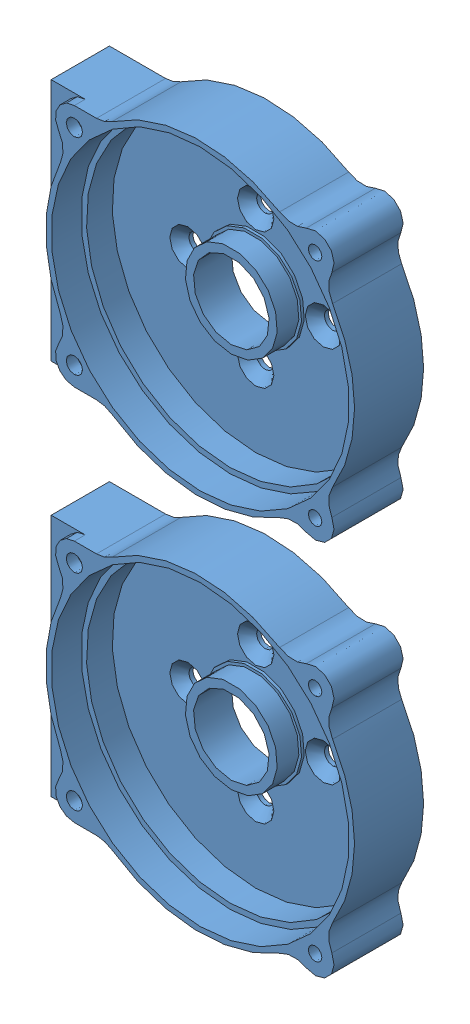
SolidWorks assembly cam3, configuration Default. Lengths in mm.
Overall size (59.75 130.14 32.25).
2 component instances, 1 part files, 3 mates.
Components (placement in the parent):
- Back Housing-2: Back Housing [Default] at (0.5773 -0.6602 10.4583) x (0 -1 0) z (0 0 -1) size (60.51 59.75 32.25)
- Back Housing-3: Back Housing [Default] at (0.5773 68.9622 10.4583) x (0 -1 0) z (0 0 -1) size (60.51 59.75 32.25)
Mates (geometry in assembly coordinates):
- Coincident1: coincident aligned: plane of Back Housing-2 through (-16.9227 -0.6602 10) normal (0 0 -1); plane of Back Housing-3 through (-16.9227 68.9622 10) normal (0 0 -1)
- Coincident4: coincident anti-aligned: plane of Back Housing-2 through (-16.9227 -0.6602 10) normal (0 0 -1); plane of assembly through (0 0 10) normal (0 0 1)
- Coincident9: coincident aligned: plane of Back Housing-2 through (-28.9227 -0.6602 69.3244) normal (-1 0 0); plane of Back Housing-3 through (-28.9227 68.9622 69.3244) normal (-1 0 0)
